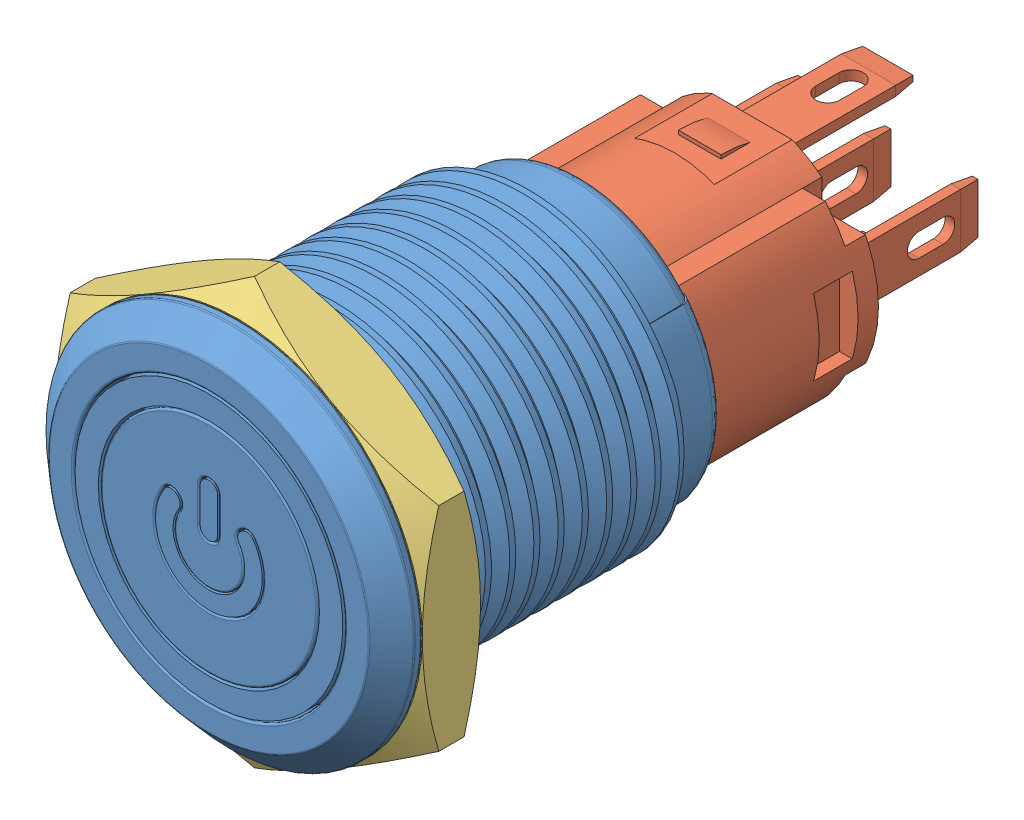
SolidWorks assembly 16mm-LED-Power-Button, configuration Default. Lengths in mm.
Overall size (19 21.94 35).
3 component instances, 3 part files, 2 mates.
Components (placement in the parent):
- Button_Body-1: Button_Body [Default] at origin size (19 19 19.3)
- Socket-1: Socket [Default] at origin size (12.92 12.92 26)
- Hex_Nut_M16-3mm-2: Hex_Nut_M16-3mm [Default] at (0 0 4.5) size (19 21.94 3.41)
Mates (geometry in assembly coordinates):
- Concentric1: concentric anti-aligned: circle of Hex_Nut_M16-3mm-2; circle of Button_Body-1
- Coincident1: coincident: plane of Button_Body-1 through (0 0 7.5) normal (0 0 -1); plane of Hex_Nut_M16-3mm-2 through (0 0 7.5) normal (0 0 1)
